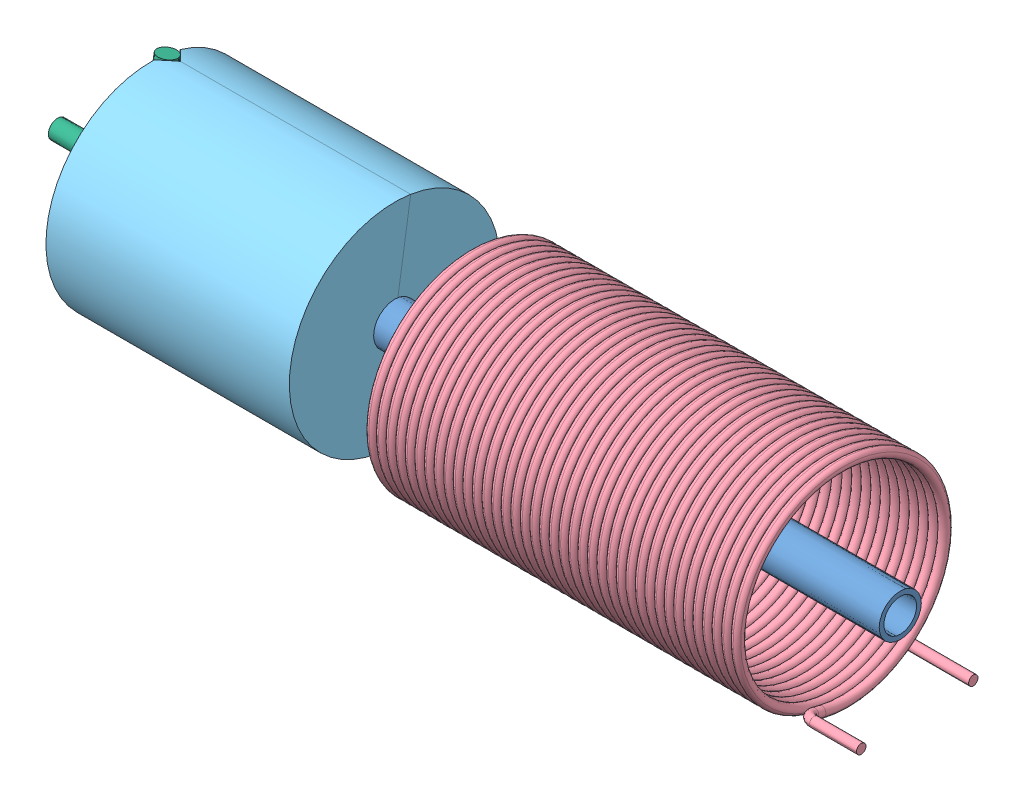
SolidWorks assembly Hydraulic Force Multiplier, configuration Default. Lengths in mm.
Overall size (90.29 33.01 33.18).
7 component instances, 6 part files, 12 mates.
Components (placement in the parent):
- Valve-1: Valve [Default] at (16.1727 25.4397 40.4014) size (74.5 20.5 20.5)
- Outer Piston-1: Outer Piston [Default] at (23.1727 25.4397 40.4014) x (1 0 0) z (0 -1 0) size (6.5 19.5 19.5)
- Inner Piston-1: Inner Piston [Default] at (12.9202 25.4397 40.4014) x (1 0 0) z (0 0.501096 0.865392) size (1 3.5 3.5)
- Electromagnet Coil-1: Electromagnet Coil [Default] at (33.4243 25.4397 40.4014) x (1 0 0) z (0 -0.60375 -0.797174) size (46.65 23.2 24.05)
- Latch-1: Latch [Default] at (24.1727 25.4174 40.4048) x (1 0 0) z (0 -0.152065 -0.988371) size (27 22.5 12.25)
- Latch-2: Latch [Default] at (24.1727 25.4174 40.4048) x (1 0 0) z (0 0.152065 0.988371) size (27 22.5 12.25)
- Latch Shaft-1: Latch Shaft [Default] at (-10.8273 25.4397 40.4014) x (-1 0 0) z (0 -0.152065 -0.988371) size (11 22.5 2)
Mates (geometry in assembly coordinates):
- Concentric1: concentric aligned: cylinder of Valve-1 through (-84.5673 25.4397 40.4014) axis (-1 0 0) radius 2.25; cylinder of Outer Piston-1 through (24.1727 25.4397 40.4014) axis (-1 0 0) radius 2.25
- Concentric2: concentric aligned: cylinder of Valve-1 through (-84.5673 25.4397 40.4014) axis (-1 0 0) radius 1.75; cylinder of Inner Piston-1 through (13.9202 25.4397 40.4014) axis (-1 0 0) radius 1.75
- Concentric3: concentric anti-aligned: cylinder of Valve-1 through (-84.5673 25.4397 40.4014) axis (-1 0 0) radius 2.25; circle of Electromagnet Coil-1
- Concentric10: concentric aligned: cylinder of Valve-1 through (19.1727 25.4397 46.4014) axis (1 0 0) radius 1; cylinder of Outer Piston-1 through (19.1727 25.4397 46.4014) axis (1 0 0) radius 1
- LimitDistance1: limit distance = 2.5 mm anti-aligned: plane of Valve-1 through (15.6727 25.4397 40.4014) normal (1 0 0); plane of Outer Piston-1 through (18.1727 25.4397 40.4014) normal (-1 0 0)
- Concentric12: concentric anti-aligned: cylinder of Latch-1 through (-0.8273 36.5366 38.6941) axis (0 -0.988371 0.152065) radius 0.5; cylinder of Latch-2 through (-0.8273 14.2982 42.1155) axis (0 0.988371 -0.152065) radius 0.5
- Coincident1: coincident anti-aligned: plane of Latch-1 through (-15.3229 33.3963 55.2743) normal (0 -0.988371 0.152065); plane of Latch-2 through (-15.3229 28.5576 23.8246) normal (0 0.988371 -0.152065)
- Concentric13: concentric aligned: cylinder of Latch-2 through (-0.8273 14.2982 42.1155) axis (0 0.988371 -0.152065) radius 0.5; cylinder of Latch Shaft-1 through (-0.8273 14.3205 42.1121) axis (0 0.988371 -0.152065) radius 0.5
- Coincident2: coincident anti-aligned: plane of Latch-2 through (-28.0509 12.7455 13.3796) normal (0 -0.988371 0.152065); circle of Latch Shaft-1
- Concentric14: concentric aligned: cylinder of Valve-1 through (-84.5673 25.4397 40.4014) axis (-1 0 0) radius 2.25; cylinder of Latch Shaft-1 through (-0.8273 25.4397 40.4014) axis (-1 0 0) radius 1
- Coincident3: coincident anti-aligned: plane of Latch-1 through (25.1727 25.4174 40.4048) normal (0 -0.152065 -0.988371); plane of Latch-2 through (25.1727 25.4174 40.4048) normal (0 0.152065 0.988371)
- Coincident4: coincident anti-aligned: plane of Outer Piston-1 through (24.6727 25.4397 40.4014) normal (1 0 0); plane of Latch-2 through (24.6727 25.4174 40.4048) normal (-1 0 0)
